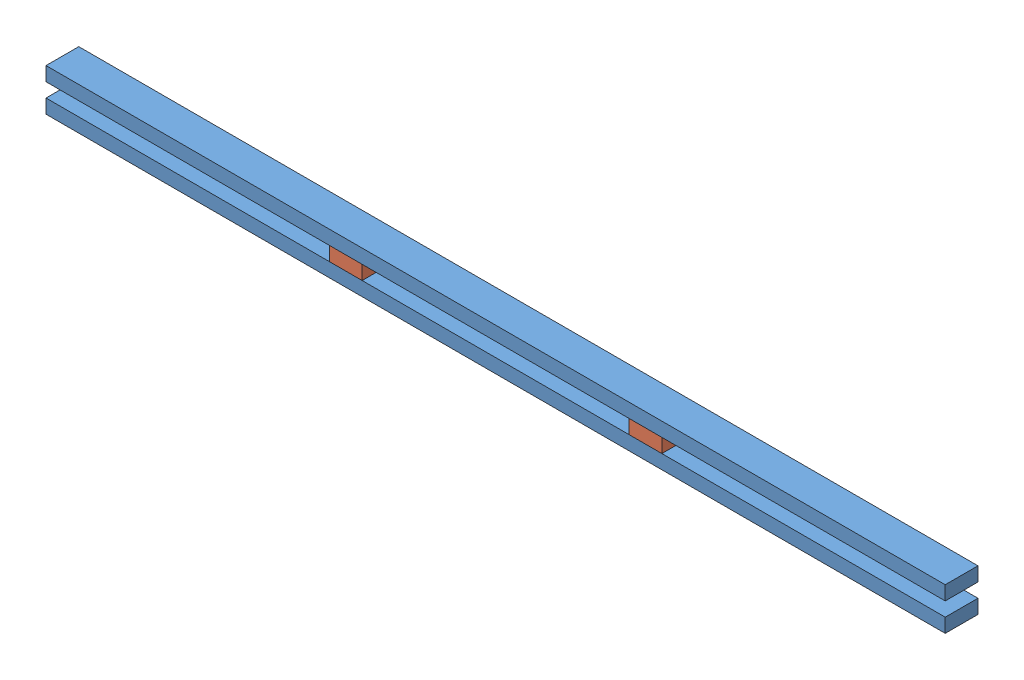
SolidWorks assembly 6x4_female_post, configuration Default. Lengths in mm.
Overall size (2438.4 114.3 88.9).
4 component instances, 2 part files, 6 mates.
Components (placement in the parent):
- 2x4-1: 2x4 [Default] at (-589.9165 1681.5327 2385.3688) size (2438.4 38.1 88.9)
- 4x4x2_gusset-1: 4x4x2_gusset [Default] at (178.4335 1719.6327 2385.3688) size (88.9 38.1 88.9)
- 4x4x2_gusset-2: 4x4x2_gusset [Default] at (991.2335 1719.6327 2385.3688) size (88.9 38.1 88.9)
- 2x4-2: 2x4 [Default] at (-589.9165 1757.7327 2385.3688) size (2438.4 38.1 88.9)
Mates (geometry in assembly coordinates):
- Coincident1: coincident: point of 2x4-1; point of 4x4x2_gusset-1
- Coincident2: coincident: plane of 2x4-1 through (-589.9165 1719.6327 2474.2688) normal (0 0 1); plane of 4x4x2_gusset-1 through (178.4335 1757.7327 2474.2688) normal (0 0 1)
- Coincident3: coincident: point of 2x4-1; point of 4x4x2_gusset-2
- Coincident4: coincident: plane of 2x4-1 through (-589.9165 1719.6327 2474.2688) normal (0 0 1); plane of 4x4x2_gusset-2 through (991.2335 1757.7327 2474.2688) normal (0 0 1)
- Coincident5: coincident: point of 4x4x2_gusset-1; point of 2x4-2
- Coincident6: coincident: plane of 4x4x2_gusset-2 through (991.2335 1757.7327 2474.2688) normal (0 0 1); plane of 2x4-2 through (-589.9165 1795.8327 2474.2688) normal (0 0 1)
